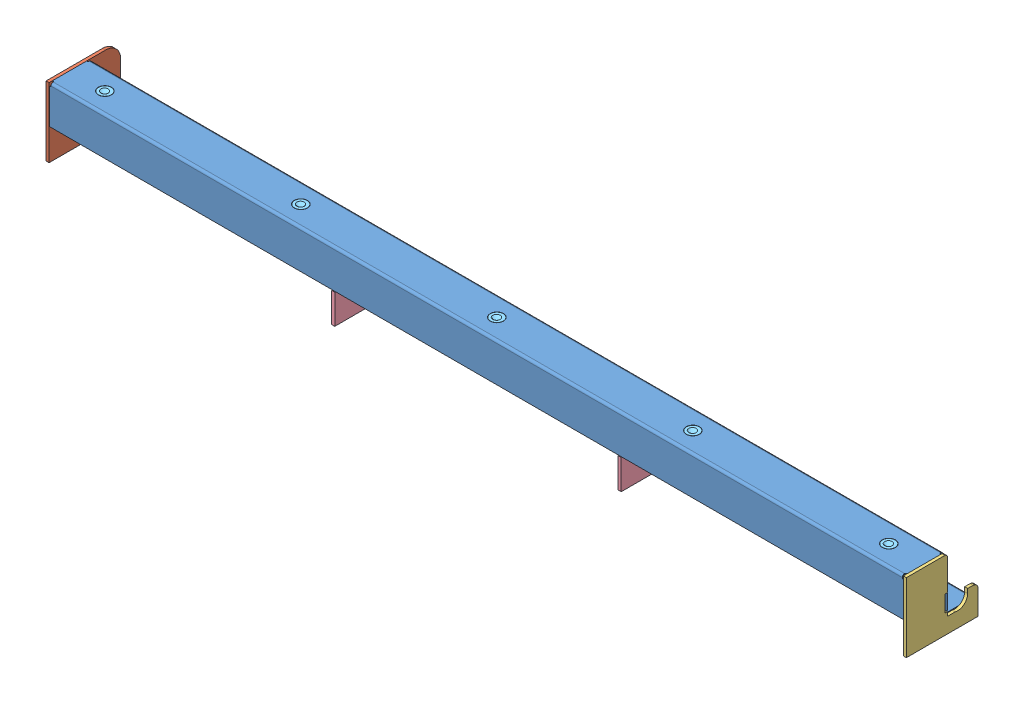
SolidWorks assembly 凸輪軌道座-左, configuration 預設. Lengths in mm.
Overall size (856 69.43 71.3).
10 component instances, 5 part files, 12 mates.
Components (placement in the parent):
- LB-A54-12-1-1: LB-A54-12-1 [預設] at (-478.7533 -41.8208 -5.1) size (856 68.08 70.64)
- LB-A54-12-4-1: LB-A54-12-4 [預設] at (-478.7533 -15.7608 35.7) x (0 0 -1) z (1 0 0) size (71.3 69 3)
- LB-A54-12-5-1: LB-A54-12-5 [預設] at (374.2467 -15.7608 35.7) x (0 0 -1) z (1 0 0) size (71.3 69 3)
- LB-A54-12-6-1: LB-A54-12-6 [預設] at (90.2467 -14.8808 35.4) x (0 0 -1) z (1 0 0) size (68.5 66.5 3)
- LB-A54-12-6-2: LB-A54-12-6 [預設] at (-194.7533 -14.8808 35.4) x (0 0 -1) z (1 0 0) size (68.5 66.5 3)
- 2分半點焊螺帽-1: 2分半點焊螺帽 [預設] at (-440.7533 45.7392 15.11) size (18.22 7.93 18.22)
- 2分半點焊螺帽-2: 2分半點焊螺帽 [預設] at (-245.7533 45.7392 15.11) size (18.22 7.93 18.22)
- 2分半點焊螺帽-3: 2分半點焊螺帽 [預設] at (-50.7533 45.7392 15.11) size (18.22 7.93 18.22)
- 2分半點焊螺帽-4: 2分半點焊螺帽 [預設] at (144.2467 45.7392 15.11) size (18.22 7.93 18.22)
- 2分半點焊螺帽-5: 2分半點焊螺帽 [預設] at (339.2467 45.7392 15.11) size (18.22 7.93 18.22)
Mates (geometry in assembly coordinates):
- 重合/共線/共點1: coincident anti-aligned: plane of LB-A54-12-1-1 through (-475.7533 51.2792 -2.8) normal (0 0 1); plane of LB-A54-12-4-1 through (-475.7533 19.4392 -2.8) normal (0 0 -1)
- 重合/共線/共點2: coincident anti-aligned: plane of LB-A54-12-1-1 through (-475.7533 15.2792 33.02) normal (-1 0 0); plane of LB-A54-12-4-1 through (-475.7533 38.2392 -20.6) normal (1 0 0)
- 重合/共線/共點3: coincident aligned: plane of LB-A54-12-1-1 through (-475.7533 53.2392 -3.14) normal (0 1 0); plane of LB-A54-12-4-1 through (-475.7533 53.2392 -20.6) normal (0 1 0)
- 重合/共線/共點4: coincident anti-aligned: plane of LB-A54-12-1-1 through (374.2467 50.9392 -1.64) normal (1 0 0); plane of LB-A54-12-5-1 through (374.2467 8.4392 -30.6) normal (-1 0 0)
- 重合/共線/共點5: coincident aligned: plane of LB-A54-12-1-1 through (-475.7533 53.2392 -3.14) normal (0 1 0); plane of LB-A54-12-5-1 through (377.2467 53.2392 -2.3) normal (0 1 0)
- 重合/共線/共點6: coincident anti-aligned: plane of LB-A54-12-1-1 through (-475.7533 51.2792 -2.8) normal (0 0 1); plane of LB-A54-12-5-1 through (377.2467 3.4392 -2.8) normal (0 0 -1)
- 重合/共線/共點7: coincident anti-aligned: plane of LB-A54-12-1-1 through (-475.7533 -2.1808 46.74) normal (0 -1 0); plane of LB-A54-12-6-1 through (93.2467 -2.1808 -30.1) normal (0 1 0)
- 重合/共線/共點8: coincident anti-aligned: plane of LB-A54-12-1-1 through (-475.7533 51.2792 -2.8) normal (0 0 1); plane of LB-A54-12-6-1 through (93.2467 -2.1808 -2.8) normal (0 0 -1)
- 平行相距1: distance = 281 mm anti-aligned: plane of LB-A54-12-5-1 through (374.2467 8.4392 -30.6) normal (-1 0 0); plane of LB-A54-12-6-1 through (93.2467 -5.1808 -30.1) normal (1 0 0)
- 同軸心1: concentric aligned: cylinder of LB-A54-12-1-1 through (-440.7533 50.9392 15.11) axis (0 1 0) radius 6.6; cylinder of 2分半點焊螺帽-1 through (-440.7533 55.7073 15.11) axis (0 1 0) radius 6.5
- 重合/共線/共點9: coincident aligned: plane of LB-A54-12-1-1 through (-475.7533 53.2392 -3.14) normal (0 1 0); plane of 2分半點焊螺帽-1 through (-440.7533 53.2392 5.9176) normal (0 1 0)
- 局部直線複製2: unknown: line of LB-A54-12-1-1 through (-474.2923 50.9392 33.02) axis (1 0 0)
